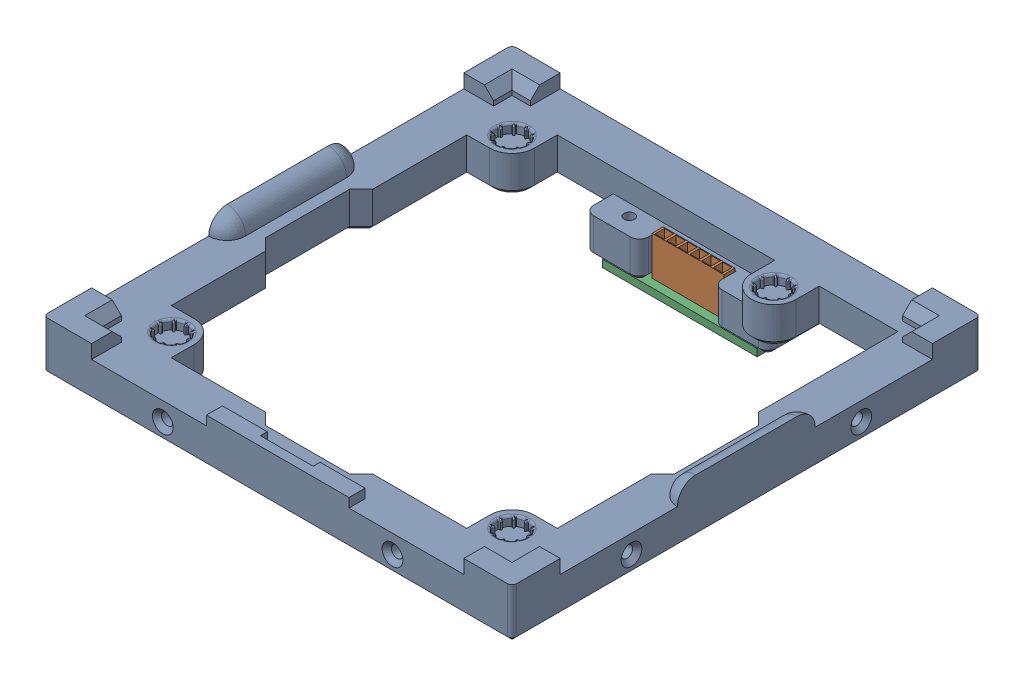
SolidWorks assembly ModuleFrameAsm, configuration Default. Lengths in mm.
Overall size (102 18.6 102).
2 component instances, 2 part files, 3 mates.
Components (placement in the parent):
- ModuleFrame-1: ModuleFrame [Default] at origin size (102 17 102)
- I2C_BusConnector-1: I2C_BusConnector [Default] at (0 -14.6 -43.0239) size (33.66 10.1 13.05)
Mates (geometry in assembly coordinates):
- Concentric3: concentric anti-aligned: circle of ModuleFrame-1; circle of I2C_BusConnector-1
- Concentric4: concentric anti-aligned: circle of ModuleFrame-1; circle of I2C_BusConnector-1
- Coincident2: coincident anti-aligned: plane of ModuleFrame-1 through (0 -13 0) normal (0 -1 0); plane of I2C_BusConnector-1 through (0 -13 -43.0239) normal (0 1 0)
